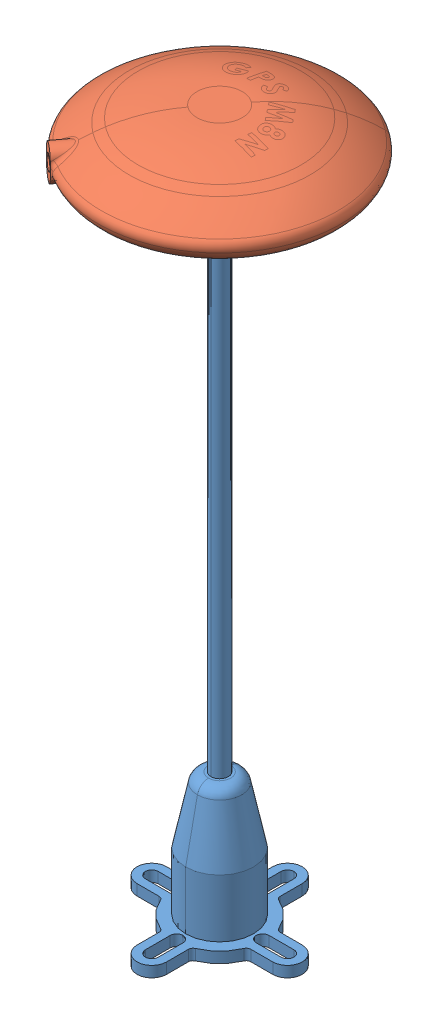
SolidWorks assembly GPS_MN8_ASM_STEP.STEP, configuration Default. Lengths in mm.
Overall size (75.84 157.4 75.99).
2 component instances, 2 part files, 0 mates.
Components (placement in the parent):
- GPS MOD_L_ _SKELET_.STEP-1: GPS MOD_L_ _SKELET_.STEP [Default] at (-10.1619 -63.6098 0) size (36.5 144.9 36.5)
- GPS M8N.STEP-1: GPS M8N.STEP [Default] at (-10.1619 81.2902 0) x (0.794386 0 0.607413) z (-0.607413 0 0.794386) size (53.76 12.5 54.56)
